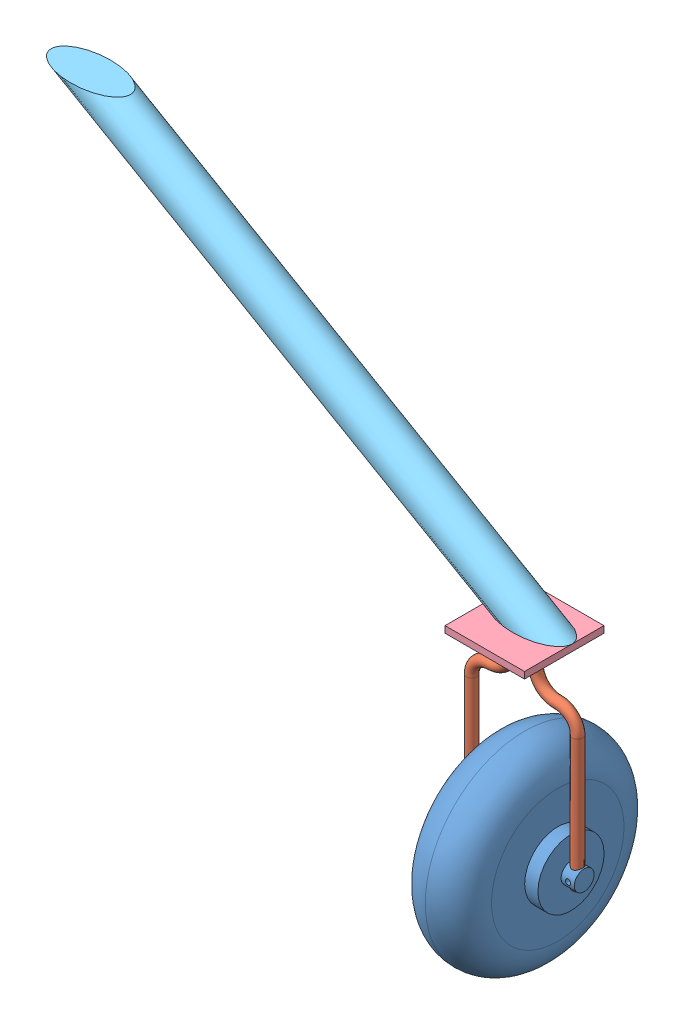
SolidWorks assembly tekermontajj, configuration Varsayılan. Lengths in mm.
Overall size (204.32 205.85 75).
8 component instances, 5 part files, 3 mates.
Components (placement in the parent):
- inişteker-1: inişteker [Varsayılan] at (200.3625 -70.0075 14.5577) size (45 109.55 75)
  - teker-1: teker [Varsayılan] at (-96.4188 18.2391 16.1212) size (45 75 75)
  - tekertutacağı-1: tekertutacağı [Varsayılan] at (-95.165 -24.524 16.138) x (-0.00479 0 -0.999989) z (0.999989 0 -0.00479) size (4.12 72.8 19.37)
  - tekertutacağı-2: tekertutacağı [Varsayılan] at (-47.6741 -24.5106 16.0152) x (0.0286 0 0.999591) z (-0.999591 0 0.0286) size (4.12 72.8 19.37)
  - tekermenteşe-1: tekermenteşe [Varsayılan] at (-66.7729 80.5024 16.5594) x (0 0 1) z (-1 0 0) size (11.94 4.5 4.93)
  - tekermenteşe-2: tekermenteşe [Varsayılan] at (-76.0587 80.5345 16.0473) x (0 0 -1) z (1 0 0) size (11.94 4.5 4.93)
  - sapbağlantı-2: sapbağlantı [Varsayılan] at (-71.4165 76.9961 16.185) x (0 0 -1) z (1 0 0) size (30 7.5 30)
- Parça1-4: Parça1 [Varsayılan] at (91.8763 49.4096 27.7271) x (-1 0 0) z (0 0 -1) size (196.8 96.3 15)
Mates (geometry in assembly coordinates):
- Paralel1: parallel: plane of inişteker-1/sapbağlantı-2 through (128.946 20.2771 30.7427) normal (0 1 0); plane of Parça1-4 through (113.9232 20.2771 44.7272) normal (0 -1 0)
- Teğet1: tangent: plane of inişteker-1/sapbağlantı-2 through (128.946 20.2771 30.7427) normal (0 1 0); curve of Parça1-4
- Kilitle1: lock: unknown of inişteker-1/sapbağlantı-2; unknown of Parça1-4
